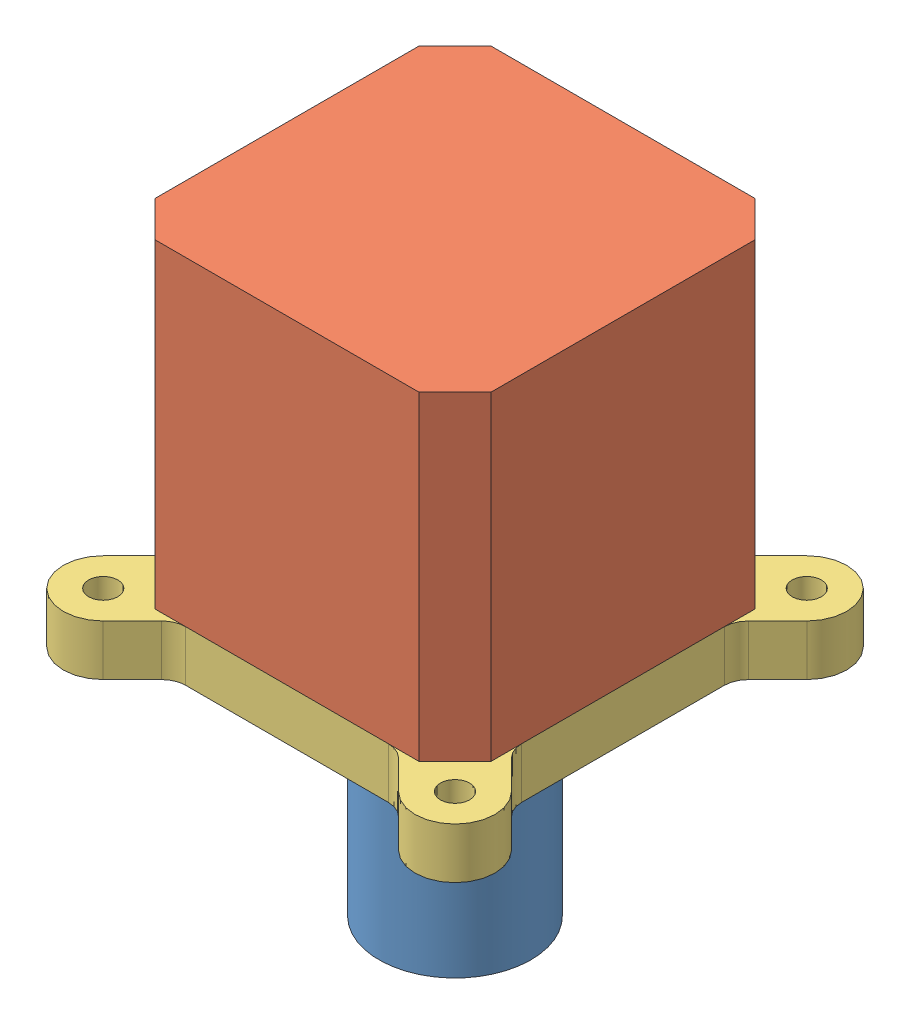
SolidWorks assembly spaced stepper motor, configuration Default. Lengths in mm.
Overall size (54 75.5 54).
7 component instances, 4 part files, 7 mates.
Components (placement in the parent):
- flexible shaft coupler-1: flexible shaft coupler [Default] at (-63.4506 -16.6619 52.7707) x (0 1 0) z (0.992962 0 -0.118432) size (25 19 19)
- nema 17 stepper motor-1: nema 17 stepper motor [Default] at (-63.4506 18.8381 52.7707) size (42 63 42)
- stepper standoff plate-1: stepper standoff plate [Default] at (-63.4506 12.4881 52.7707) size (54 6.35 54)
- 91292A113-m3 10mm bolt-1: 91292A113-m3 10mm bolt [91292A113] at (-78.9506 22.4881 68.2707) x (0.837169 0 0.546944) z (0 1 0) size (5.5 5.5 13.21)
- 91292A113-m3 10mm bolt-2: 91292A113-m3 10mm bolt [91292A113] at (-47.9506 22.4881 37.2707) x (0.837169 0 0.546944) z (0 1 0) size (5.5 5.5 13.21)
- 91292A113-m3 10mm bolt-3: 91292A113-m3 10mm bolt [91292A113] at (-47.9506 22.4881 68.2707) x (0.837169 0 0.546944) z (0 1 0) size (5.5 5.5 13.21)
- 91292A113-m3 10mm bolt-4: 91292A113-m3 10mm bolt [91292A113] at (-78.9506 22.4881 37.2707) x (0.837169 0 0.546944) z (0 1 0) size (5.5 5.5 13.21)
Mates (geometry in assembly coordinates):
- Coincident1: coincident: plane of nema 17 stepper motor-1 through (-63.4506 18.8381 52.7707) normal (0 -1 0); plane of stepper standoff plate-1 through (-63.4506 18.8381 52.7707) normal (0 1 0)
- Concentric1: concentric: circle of nema 17 stepper motor-1; circle of stepper standoff plate-1
- Concentric2: concentric: circle of nema 17 stepper motor-1; circle of stepper standoff plate-1
- Concentric3: concentric: cylinder of flexible shaft coupler-1 through (-63.4506 -4.1619 52.7707) axis (0 1 0) radius 2.5; cylinder of nema 17 stepper motor-1 through (-63.4506 -4.1619 52.7707) axis (0 1 0) radius 2.5
- Coincident2: coincident: plane of flexible shaft coupler-1 through (-63.4506 -4.1619 52.7707) normal (0 -1 0); plane of nema 17 stepper motor-1 through (-63.4506 -4.1619 52.7707) normal (0 -1 0)
- Concentric4: concentric: cylinder of stepper standoff plate-1 through (-78.9506 18.8381 68.2707) axis (0 1 0) radius 1.6; cylinder of 91292A113-m3 10mm bolt-1 through (-78.9506 9.4881 68.2707) axis (0 1 0) radius 2.75
- Coincident3: coincident: plane of stepper standoff plate-1 through (-63.4506 12.4881 52.7707) normal (0 -1 0); plane of 91292A113-m3 10mm bolt-1 through (-78.9506 12.4881 68.2707) normal (0 1 0)
